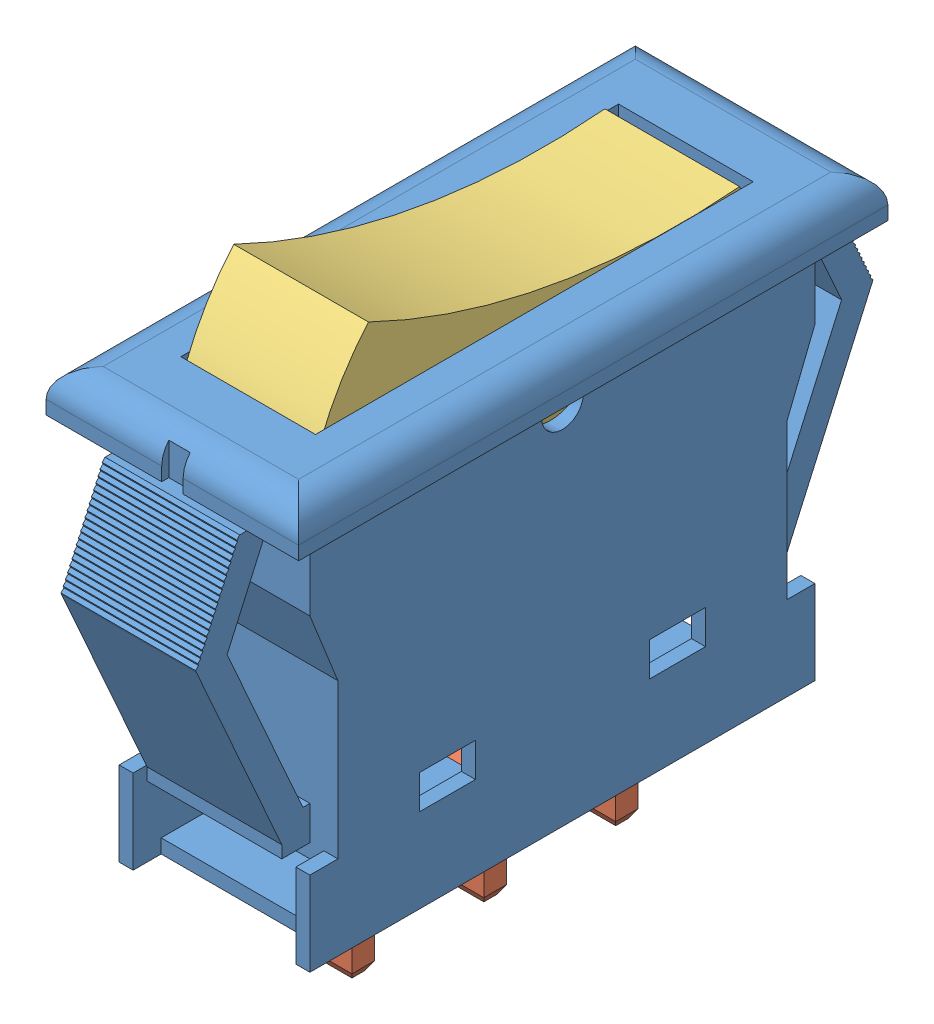
SolidWorks assembly Rocker Switch, configuration Default. Lengths in mm.
Overall size (9 21.76 24.15).
5 component instances, 3 part files, 12 mates.
Components (placement in the parent):
- Rocker Switch Body-1: Rocker Switch Body [Default] at (0 -4.9517 5.8721) size (9 15.5 24.15)
- Rocker Switch Lead-1: Rocker Switch Lead [Default] at (1 -4.4517 1.1721) x (1 0 0) z (0 0 -1) size (2 4 0.8)
- Rocker Switch Lead-2: Rocker Switch Lead [Default] at (1 -4.4517 -3.5279) x (1 0 0) z (0 0 -1) size (2 4 0.8)
- Rocker Switch Lead-3: Rocker Switch Lead [Default] at (1 -4.4517 -8.2279) x (1 0 0) z (0 0 -1) size (2 4 0.8)
- Rocker Switch Rocker-1: Rocker Switch Rocker [Default] at (0 8.5128 4.9209) x (1 0 0) z (0 0.180999 0.983483) size (6.8 4.88 16)
Mates (geometry in assembly coordinates):
- Coincident1: coincident anti-aligned: plane of Rocker Switch Body-1 through (-1 10.5493 1.9721) normal (0 0 -1); plane of Rocker Switch Lead-1 through (1 -8.4517 1.9721) normal (0 0 1)
- Coincident2: coincident anti-aligned: plane of Rocker Switch Body-1 through (1 10.5493 1.9721) normal (-1 0 0); plane of Rocker Switch Lead-1 through (1 -8.4517 1.1721) normal (1 0 0)
- Coincident3: coincident aligned: plane of Rocker Switch Body-1 through (-3.4 -4.4517 -12.1279) normal (0 1 0); plane of Rocker Switch Lead-1 through (1 -4.4517 1.1721) normal (0 1 0)
- Coincident4: coincident anti-aligned: plane of Rocker Switch Body-1 through (-1 10.5493 -2.7279) normal (0 0 -1); plane of Rocker Switch Lead-2 through (1 -8.4517 -2.7279) normal (0 0 1)
- Coincident5: coincident anti-aligned: plane of Rocker Switch Body-1 through (-1 10.5493 -2.7279) normal (1 0 0); plane of Rocker Switch Lead-2 through (-1 -8.4517 -3.5279) normal (-1 0 0)
- Coincident6: coincident aligned: plane of Rocker Switch Body-1 through (-3.4 -4.4517 -12.1279) normal (0 1 0); plane of Rocker Switch Lead-2 through (1 -4.4517 -3.5279) normal (0 1 0)
- Coincident7: coincident anti-aligned: plane of Rocker Switch Body-1 through (-1 10.5493 -7.4279) normal (0 0 -1); plane of Rocker Switch Lead-3 through (1 -8.4517 -7.4279) normal (0 0 1)
- Coincident8: coincident anti-aligned: plane of Rocker Switch Body-1 through (-1 10.5493 -8.2279) normal (1 0 0); plane of Rocker Switch Lead-3 through (-1 -8.4517 -8.2279) normal (-1 0 0)
- Coincident9: coincident aligned: plane of Rocker Switch Body-1 through (-3.4 -4.4517 -12.1279) normal (0 1 0); plane of Rocker Switch Lead-3 through (1 -4.4517 -8.2279) normal (0 1 0)
- Concentric1: concentric anti-aligned: cylinder of Rocker Switch Body-1 through (-4.5 8.0483 -3.1279) axis (1 0 0) radius 0.75; cylinder of Rocker Switch Rocker-1 through (3.4 8.0483 -3.1279) axis (-1 0 0) radius 0.75
- Coincident10: coincident anti-aligned: plane of Rocker Switch Body-1 through (2.4 9.7983 4.6721) normal (-1 0 0); plane of Rocker Switch Rocker-1 through (2.4 7.3609 -1.5012) normal (1 0 0)
- Tangent1: tangent anti-aligned: plane of Rocker Switch Body-1 through (-4.5 10.5483 -13.6279) normal (0 1 0); cylinder of Rocker Switch Rocker-1 through (2.4 35.9483 -8.2626) axis (-1 0 0) radius 25.4
